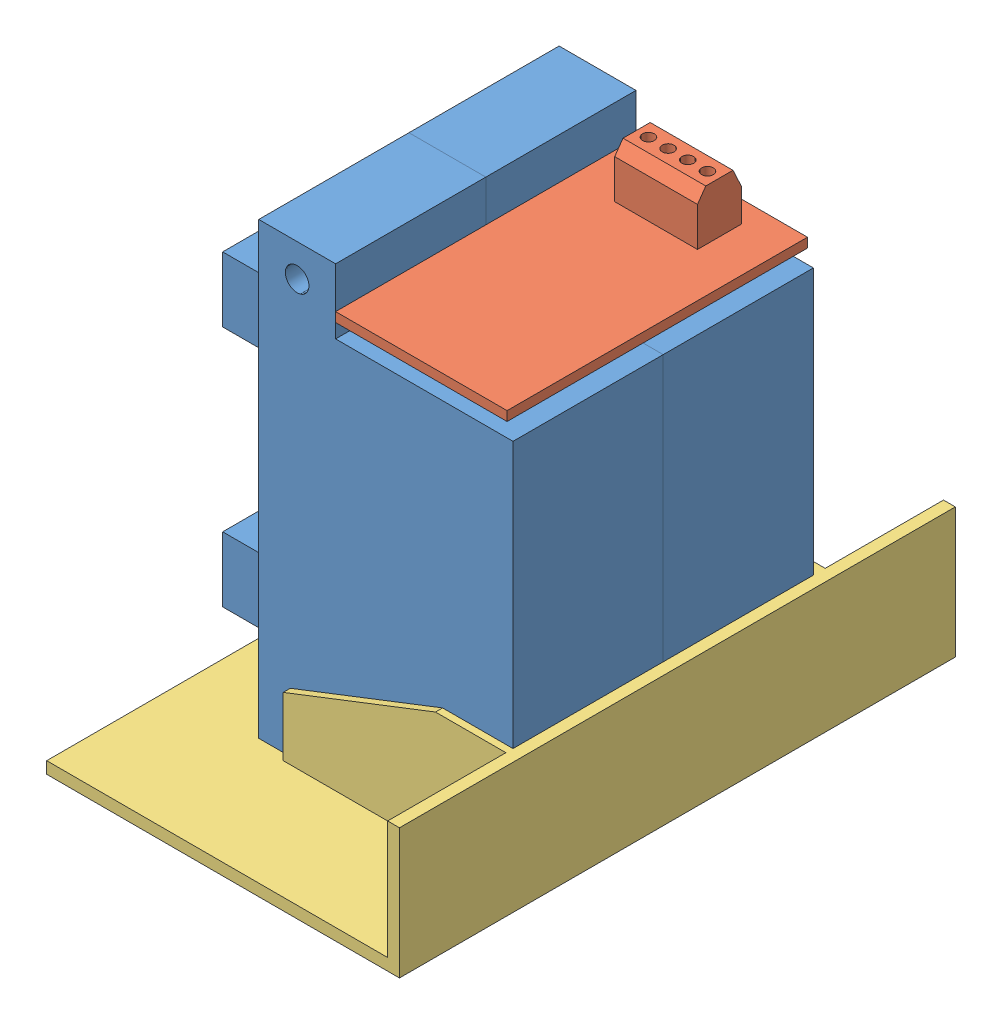
SolidWorks assembly 123SmartRelay, configuration Predeterminado. Lengths in mm.
Overall size (59.66 79.6 94).
4 component instances, 3 part files, 9 mates.
Components (placement in the parent):
- Relay200A-1: Relay200A [Predeterminado] at origin size (53.3 76 25.4)
- Relay200A-2: Relay200A [Predeterminado] at (0 0 -25.4) size (53.3 76 25.4)
- PCB_relays-1: PCB_relays [Predeterminado] at (27.5 67.4 -12.7) size (29 10.2 50.8)
- base relay-1: base relay [Predeterminado] at (43 0 -13.1) x (0 0 -1) z (1 0 0) size (94 22 59.66)
Mates (geometry in assembly coordinates):
- Coincidente1: coincident: plane of Relay200A-1 through (43 0 12.7) normal (1 0 0); plane of Relay200A-2 through (43 0 -12.7) normal (1 0 0)
- Coincidente2: coincident: plane of Relay200A-1 through (0 0 -12.7) normal (0 0 -1); plane of Relay200A-2 through (0 0 -12.7) normal (0 0 1)
- Coincidente3: coincident aligned: plane of Relay200A-1 through (0 0 12.7) normal (0 -1 0); plane of Relay200A-2 through (0 0 -12.7) normal (0 -1 0)
- Coincidente4: coincident: plane of Relay200A-1 through (13 65 12.7) normal (1 0 0); plane of PCB_relays-1 through (13 72.4566 -38.1) normal (-1 0 0)
- Ancho1: width: plane of Relay200A-1 through (0 0 12.7) normal (0 0 1); plane of Relay200A-2 through (0 0 -38.1) normal (0 0 -1); plane of PCB_relays-1 through (13 69 12.7) normal (0 0 1); plane of PCB_relays-1 through (13 69 -38.1) normal (0 0 -1)
- Distancia1: distance = 4 mm aligned: plane of PCB_relays-1 through (27.5 69 -12.7) normal (0 1 0); plane of Relay200A-2 through (13 65 -12.7) normal (0 1 0)
- Coincidente5: coincident: plane of Relay200A-1 through (0 0 12.7) normal (0 -1 0); plane of base relay-1 through (43 0 -13.1) normal (0 1 0)
- Coincidente6: coincident: plane of Relay200A-2 through (43 0 -12.7) normal (1 0 0); plane of base relay-1 through (43 0 -13.1) normal (-1 0 0)
- Coincidente7: coincident anti-aligned: plane of Relay200A-2 through (0 0 -38.1) normal (0 0 -1); plane of base relay-1 through (43 -61.4144 -38.1) normal (0 0 1)
